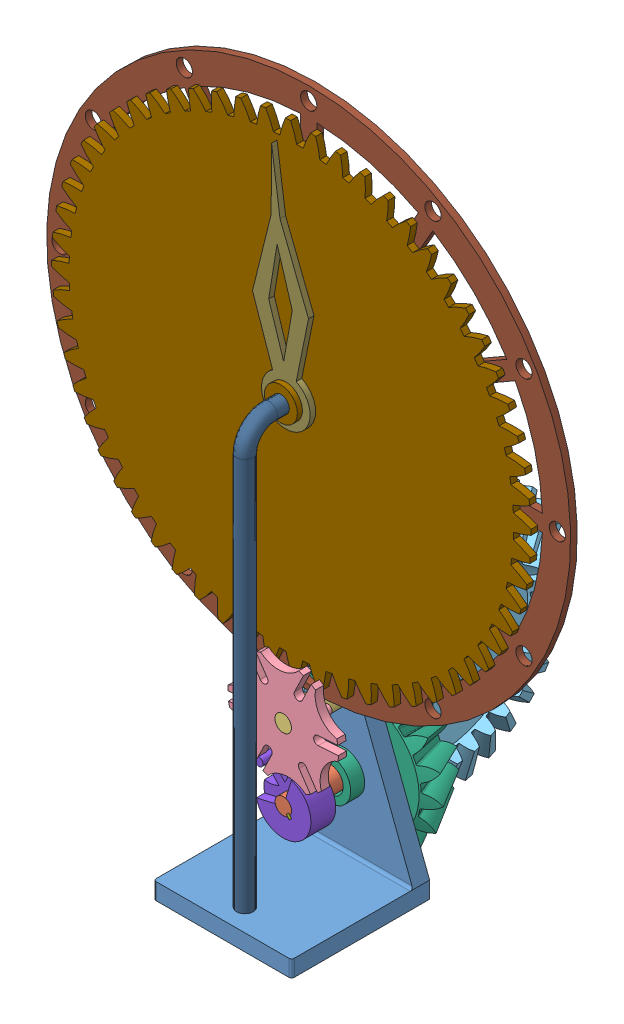
SolidWorks assembly Exp_ver, configuration Default. Lengths in mm.
Overall size (948.87 1447.19 1118.23).
12 component instances, 12 part files, 31 mates.
Components (placement in the parent):
- base-1: base [Default] at (0.0366 0 125) size (250 320 250)
- stift-1: stift [Default] at (0.0868 153.43 70) x (-0.731193 -0.68217 0) z (-0.68217 0.731193 0) size (40 140 40)
- stift2-1: stift2 [Default] at (-0.1503 283.43 70) x (1 0 0) z (0 1 0) size (40 140 40)
- wheel 1-2: wheel 1 [Default] at (-0.1503 283.43 132.5) x (0.06957 -0.997577 0) z (0.997577 0.06957 0) size (187.69 25 199.4)
- straight bevel gear_iso-2: straight bevel gear_iso [ISO - Straight bevel gear 14M 34GT 17PT 20PA 80FW ---34O200H300MD80.0R1] at (-142.9095 153.43 -244.5981) x (1 0 0) z (0 0.787659 -0.616111) size (225.99 484.15 485.02)
- straight bevel pinion_iso-2: straight bevel pinion_iso [ISO - Straight bevel pinion 14M17PT 34GT 20PA 80FW ---17O75H300MD48.0R1] at (0.0868 153.43 0) x (0 0 -1) z (0.731193 0.68217 0) size (142.55 269.77 270.92)
- Pin-1: Pin [Default] at (10.3194 142.4621 95) x (-0.731193 -0.68217 0) z (-0.68217 0.731193 0) size (6 45 8)
- wheel 2-2: wheel 2 [Default] at (0.0868 153.43 125) x (-0.68217 0.731193 0) z (0.731193 0.68217 0) size (122.5 45 100)
- spur gear_am-4: spur gear_am [Metric - Spur gear 14M 60T 20PA 12FW ---S60B60H50L0.8N] at (-0.3634 786.0276 113) x (0 0 1) z (0.997818 0.066025 0) size (50 867.25 867.25)
- TUBE-7: TUBE [Default] at (0.0366 1036.768 638.469) x (0 0.887813 -0.460204) z (-1 0 0) size (799.82 374.73 30)
- clock marking-1: clock marking [Default] at (0.0366 786.0277 82) x (1 -0.000005 0) z (-0.000005 -1 0) size (948.86 12 948.86)
- TUBE2-1: TUBE2 [Default] at (-0.3634 786.0276 135) x (-0.997818 -0.066025 0) z (0.066025 -0.997818 0) size (101.62 10 436.16)
Mates (geometry in assembly coordinates):
- Coincident1: coincident: plane of assembly through (0 0 0) normal (0 1 0); plane of base-1 through (125.0366 0 250) normal (0 -1 0); plane of assembly
- Coincident2: coincident: plane of assembly through (0 0 0) normal (0 0 1); plane of base-1 through (-124.9634 30 0) normal (0 0 -1); plane of assembly
- Concentric2: concentric: cylinder of base-1 through (-0.1503 283.43 0) axis (0 0 1) radius 15; cylinder of stift2-1 through (-0.1503 283.43 140) axis (0 0 -1) radius 15
- Coincident3: coincident: plane of base-1 through (0.0366 300 30) normal (0 0 1); plane of stift2-1 through (-0.1503 283.43 30) normal (0 0 -1)
- Concentric3: concentric: cylinder of base-1 through (0.0868 153.43 0) axis (0 0 1) radius 15; cylinder of stift-1 through (0.0868 153.43 140) axis (0 0 -1) radius 15
- Coincident4: coincident: plane of base-1 through (0.0366 300 30) normal (0 0 1); plane of stift-1 through (0.0868 153.43 30) normal (0 0 -1)
- Concentric8: concentric: cylinder of stift2-1 through (-0.1503 283.43 140) axis (0 0 -1) radius 15; cylinder of wheel 1-2 through (-0.1503 283.43 125) axis (0 0 1) radius 15
- Coincident29: coincident: plane of stift2-1 through (-0.1503 283.43 125) normal (0 0 1); plane of wheel 1-2 through (-0.1503 283.43 125) normal (0 0 -1)
- Coincident6: coincident: point of straight bevel gear_iso-2; point of straight bevel pinion_iso-2
- Perpendicular1: perpendicular: line of straight bevel gear_iso-2 through (-152.9095 153.43 -244.5981) axis (1 0 0); line of straight bevel pinion_iso-2 through (0.0868 153.43 0) axis (0 0 -1)
- Parallel3: parallel: plane of assembly through (0 0 0) normal (1 0 0); plane of straight bevel gear_iso-2 through (-299.9133 153.43 -244.5981) normal (-1 0 0); plane of assembly
- Coincident36: coincident: plane of base-1 through (-124.9634 30 0) normal (0 0 -1); plane of straight bevel pinion_iso-2 through (0.0868 153.43 0) normal (0 0 1)
- Concentric13: concentric: cylinder of stift-1 through (0.0868 153.43 110) axis (0 0 -1) radius 20; cylinder of straight bevel pinion_iso-2 through (0.0868 153.43 -300.0001) axis (0 0 1) radius 24
- Coincident38: coincident: plane of stift-1 through (0.0868 153.43 70) normal (-0.68217 0.731193 0); plane of straight bevel pinion_iso-2 through (0.0868 153.43 0) normal (-0.68217 0.731193 0)
- Coincident44: coincident: plane of stift-1 through (9.7843 147.4333 85) normal (0.68217 -0.731193 0); plane of Pin-1 through (9.7843 147.4333 140) normal (-0.68217 0.731193 0)
- Coincident49: coincident: plane of stift-1 through (0.0868 153.43 95) normal (0 0 1); plane of Pin-1 through (10.3194 142.4621 95) normal (0 0 -1)
- Coincident52: coincident: plane of stift-1 through (0.0868 153.43 95) normal (0 0 1); plane of wheel 2-2 through (0.0868 153.43 95) normal (0 0 -1)
- Coincident53: coincident: plane of stift-1 through (0.0868 153.43 95) normal (0 0 1); plane of wheel 2-2 through (0.0868 153.43 95) normal (0 0 -1)
- Concentric16: concentric: cylinder of stift-1 through (0.0868 153.43 140) axis (0 0 -1) radius 15; cylinder of wheel 2-2 through (0.0868 153.43 140) axis (0 0 -1) radius 15
- Coincident54: coincident: plane of Pin-1 through (15.2416 141.5838 140) normal (0.68217 -0.731193 0); plane of wheel 2-2 through (10.8545 137.4908 95) normal (-0.68217 0.731193 0)
- Coincident55: coincident: plane of Pin-1 through (10.8545 137.4908 140) normal (-0.731193 -0.68217 0); plane of wheel 2-2 through (10.8545 137.4908 95) normal (0.731193 0.68217 0)
- Coincident62: coincident: plane of wheel 1-2 through (-0.1503 283.43 125) normal (0 0 -1); plane of spur gear_am-4 through (-0.36 785.9757 125) normal (0 0 1)
- Concentric41: concentric: cylinder of base-1 through (0.0366 0 209.5077) axis (0 1 0) radius 15; cylinder of TUBE-7 through (0.0366 944.7777 209.5077) axis (0 -1 0) radius 15
- Coincident79: coincident: plane of base-1 through (125.0366 0 250) normal (0 -1 0); plane of TUBE-7 through (0.0366 0 209.5077) normal (0 -1 0)
- Concentric42: concentric: cylinder of spur gear_am-4 through (0.04 785.9759 64) axis (0 0 1) radius 15; cylinder of TUBE-7 through (0.0366 786.0277 31.8609) axis (0 0 1) radius 15
- Coincident80: coincident: plane of spur gear_am-4 through (-0.36 785.9757 94) normal (0 0 -1); plane of clock marking-1 through (0.0366 786.0277 94) normal (0 0 1)
- Concentric43: concentric: cylinder of TUBE-7 through (0.0366 786.0277 31.8609) axis (0 0 1) radius 15; cylinder of clock marking-1 through (0.0366 786.0277 94) axis (0 0 -1) radius 15
- Coincident82: coincident: plane of spur gear_am-4 through (-0.36 785.9757 125) normal (0 0 1); plane of TUBE2-1 through (-0.36 785.9757 125) normal (0 0 -1)
- Concentric44: concentric: cylinder of spur gear_am-4 through (-0.36 785.9757 144) axis (0 0 -1) radius 30; cylinder of TUBE2-1 through (-0.36 785.9757 125) axis (0 0 1) radius 30
- Coincident84: coincident: plane of spur gear_am-4 through (-0.36 785.9757 113) normal (0.066025 -0.997818 0); plane of TUBE2-1 through (-0.36 785.9757 135) normal (0.066025 -0.997818 0)
- Perpendicular2: perpendicular: plane of spur gear_am-4 through (-0.36 785.9757 113) normal (0 0 1); plane of TUBE2-1 through (-0.36 785.9757 135) normal (0.066025 -0.997818 0)
